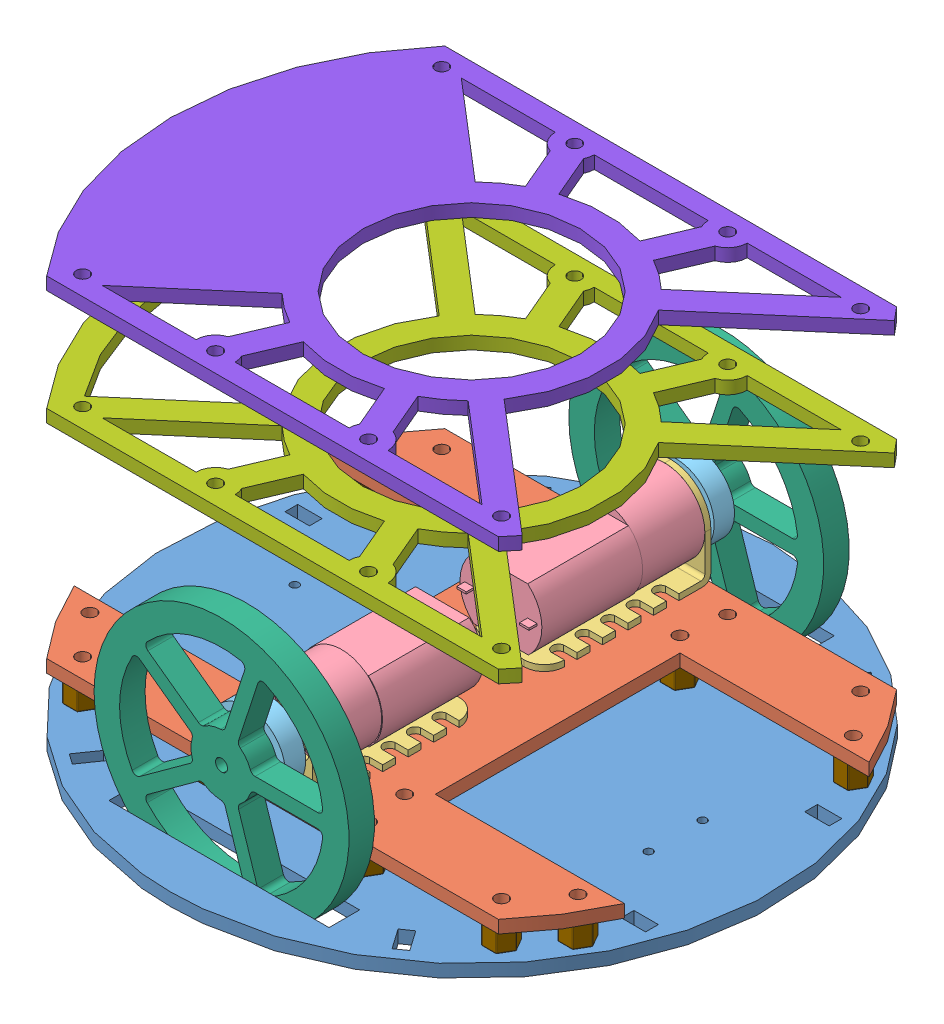
SolidWorks assembly Assembly, configuration Default. Lengths in mm.
Overall size (150 102.8 150).
30 component instances, 9 part files, 36 mates.
Components (placement in the parent):
- Bottom-1: Bottom [Default] at (46.4313 73.5336 122.3273) size (150 3.17 150)
- WheelPlatform-1: WheelPlatform [Default] at (46.4313 83.0586 122.3273) size (137.05 3.17 99.19)
- Pololu_bracket-1: Pololu_bracket [Default] at (36.4313 86.2336 171.9215) x (0 0 -1) z (1 0 0) size (41.5 21.5 20)
- Pololu_29to1-1: Pololu_29to1 [Default] at (46.4313 97.7336 154.7215) size (20.4 20 53.45)
- Pololu_4mm_MountingHub-1: Pololu_4mm_MountingHub [Default] at (46.4313 97.7336 178.2815) x (0 -1 0) z (0 0 -1) size (19.05 19.05 5.08)
- Wheel-1: Wheel [Default] at (46.4313 97.7336 184.6315) x (0 -1 0) z (1 0 0) size (63.5 6.35 63.5)
- Wheel-2: Wheel [Default] at (46.4313 97.7336 60.0231) x (0 1 0) z (1 0 0) size (63.5 6.35 63.5)
- Pololu_4mm_MountingHub-2: Pololu_4mm_MountingHub [Default] at (46.4313 97.7336 71.4531) x (0 -1 0) z (0 0 -1) size (19.05 19.05 5.08)
- Pololu_29to1-2: Pololu_29to1 [Default] at (46.4313 97.7336 89.9331) x (-1 0 0) z (0 0 -1) size (20.4 20 53.45)
- Pololu_bracket-2: Pololu_bracket [Default] at (56.4313 86.2336 72.7331) x (0 0 1) z (-1 0 0) size (41.5 21.5 20)
- CanBottom-1: CanBottom [Default] at (46.4313 137.0336 122.3273) size (133.96 3.17 99.19)
- CanMiddle-1: CanMiddle [Default] at (46.4313 165.6086 122.3273) size (133.96 3.17 99.19)
- Standoff-1: Standoff [Default] at (-5.749 76.7086 167.0571) size (7.25 6.35 6.35)
- Standoff-2: Standoff [Default] at (-14.3605 76.7086 156.6173) size (7.25 6.35 6.35)
- Standoff-3: Standoff [Default] at (27.3813 76.7086 167.0571) x (0.5 0 0.866025) z (-0.866025 0 0.5) size (7.25 6.35 6.35)
- Standoff-4: Standoff [Default] at (28.8195 76.7086 156.6173) size (7.25 6.35 6.35)
- Standoff-5: Standoff [Default] at (98.6116 76.7086 167.0571) x (-1 0 0) z (0 0 -1) size (7.25 6.35 6.35)
- Standoff-6: Standoff [Default] at (107.2231 76.7086 156.6173) x (-1 0 0) z (0 0 -1) size (7.25 6.35 6.35)
- Standoff-7: Standoff [Default] at (65.4813 76.7086 167.0571) x (-0.5 0 0.866025) z (-0.866025 0 -0.5) size (7.25 6.35 6.35)
- Standoff-8: Standoff [Default] at (64.0431 76.7086 156.6173) x (-1 0 0) z (0 0 -1) size (7.25 6.35 6.35)
- Standoff-9: Standoff [Default] at (46.4313 76.7086 133.8215) size (7.25 6.35 6.35)
- Standoff-10: Standoff [Default] at (98.6116 76.7086 77.5974) x (-1 0 0) z (0 0 -1) size (7.25 6.35 6.35)
- Standoff-11: Standoff [Default] at (107.2231 76.7086 88.0373) x (-1 0 0) z (0 0 -1) size (7.25 6.35 6.35)
- Standoff-12: Standoff [Default] at (65.4813 76.7086 77.5974) x (-0.5 0 -0.866025) z (0.866025 0 -0.5) size (7.25 6.35 6.35)
- Standoff-13: Standoff [Default] at (64.0431 76.7086 88.0373) x (-1 0 0) z (0 0 -1) size (7.25 6.35 6.35)
- Standoff-14: Standoff [Default] at (-5.749 76.7086 77.5974) size (7.25 6.35 6.35)
- Standoff-15: Standoff [Default] at (27.3813 76.7086 77.5974) x (0.5 0 -0.866025) z (0.866025 0 0.5) size (7.25 6.35 6.35)
- Standoff-16: Standoff [Default] at (-14.3605 76.7086 88.0373) size (7.25 6.35 6.35)
- Standoff-17: Standoff [Default] at (28.8195 76.7086 88.0373) size (7.25 6.35 6.35)
- Standoff-18: Standoff [Default] at (46.4313 76.7086 110.8331) size (7.25 6.35 6.35)
Mates (geometry in assembly coordinates):
- Concentric1: concentric aligned: cylinder of Bottom-1 through (46.4313 76.7086 122.3273) axis (0 -1 0) radius 75; cylinder of WheelPlatform-1 through (46.4313 86.2336 122.3273) axis (0 -1 0) radius 75
- Distance1: distance = 6.35 mm anti-aligned: plane of Bottom-1 through (46.4313 76.7086 122.3273) normal (0 1 0); plane of WheelPlatform-1 through (46.4313 83.0586 122.3273) normal (0 -1 0)
- Parallel1: parallel aligned: plane of Bottom-1 through (19.0182 18.1804 177.6465) normal (0 0 1); plane of WheelPlatform-1 through (-9.8307 -32.2979 171.9215) normal (0 0 1)
- Concentric2: concentric anti-aligned: cylinder of Pololu_bracket-1 through (46.4313 97.7336 130.4215) axis (0 0 1) radius 3.75; cylinder of Pololu_29to1-1 through (46.4313 97.7336 173.2015) axis (0 0 -1) radius 3.5
- Concentric3: concentric aligned: cylinder of Pololu_bracket-1 through (46.4313 105.2336 130.4215) axis (0 0 1) radius 1.45; cylinder of Pololu_29to1-1 through (46.4313 105.2336 170.4215) axis (0 0 1) radius 1.025
- Coincident8: coincident anti-aligned: plane of Pololu_bracket-1 through (56.4313 87.7336 170.4215) normal (0 0 -1); plane of Pololu_29to1-1 through (46.4313 97.7336 170.4215) normal (0 0 1)
- Concentric4: concentric anti-aligned: cylinder of Pololu_29to1-1 through (46.4313 97.7336 181.0715) axis (0 0 -1) radius 2; cylinder of Pololu_4mm_MountingHub-1 through (46.4313 97.7336 173.2015) axis (0 0 1) radius 2
- Coincident9: coincident anti-aligned: plane of Pololu_29to1-1 through (46.4313 97.7336 154.7215) normal (1 0 0); plane of Pololu_4mm_MountingHub-1
- Coincident10: coincident anti-aligned: plane of Pololu_29to1-1 through (46.4313 97.7336 173.2015) normal (0 0 1); plane of Pololu_4mm_MountingHub-1 through (46.4313 97.7336 173.2015) normal (0 0 -1)
- Concentric6: concentric anti-aligned: cylinder of Pololu_29to1-1 through (46.4313 97.7336 181.0715) axis (0 0 -1) radius 2; cylinder of Wheel-1 through (46.4313 97.7336 178.2815) axis (0 0 1) radius 1.5
- Coincident11: coincident anti-aligned: plane of Pololu_4mm_MountingHub-1 through (46.4313 97.7336 178.2815) normal (0 0 1); plane of Wheel-1 through (46.4313 97.7336 178.2815) normal (0 0 -1)
- Coincident12: coincident anti-aligned: plane of Pololu_4mm_MountingHub-1; plane of Wheel-1 through (46.4313 97.7336 184.6315) normal (1 0 0)
- Coincident14: coincident anti-aligned: plane of WheelPlatform-1 through (46.4313 86.2336 122.3273) normal (0 1 0); plane of Pololu_bracket-1 through (56.4313 86.2336 171.9215) normal (0 -1 0)
- Coincident15: coincident anti-aligned: plane of Bottom-1 through (46.4313 73.5336 181.4565) normal (0 0 1); plane of Wheel-1
- Coincident16: coincident aligned: plane of WheelPlatform-1 through (46.4313 83.0586 122.3273) normal (1 0 0); plane of Pololu_29to1-1 through (46.4313 97.7336 154.7215) normal (1 0 0)
- Concentric7: concentric aligned: cylinder of Bottom-1 through (46.4313 76.7086 122.3273) axis (0 -1 0) radius 75; cylinder of CanBottom-1 through (46.4313 140.2086 122.3273) axis (0 -1 0) radius 75
- Distance2: distance = 50.8 mm anti-aligned: plane of WheelPlatform-1 through (46.4313 86.2336 122.3273) normal (0 1 0); plane of CanBottom-1 through (46.4313 137.0336 122.3273) normal (0 -1 0)
- Parallel2: parallel aligned: plane of WheelPlatform-1 through (-9.8307 -32.2979 171.9215) normal (0 0 1); plane of CanBottom-1 through (-9.8307 21.6771 171.9215) normal (0 0 1)
- Concentric8: concentric aligned: cylinder of Bottom-1 through (46.4313 76.7086 122.3273) axis (0 -1 0) radius 75; cylinder of CanMiddle-1 through (46.4313 168.7836 122.3273) axis (0 -1 0) radius 75
- Coincident19: coincident aligned: plane of CanBottom-1 through (-9.8307 21.6771 171.9215) normal (0 0 1); plane of CanMiddle-1 through (-9.8307 50.2521 171.9215) normal (0 0 1)
- Distance3: distance = 25.4 mm anti-aligned: plane of CanBottom-1 through (46.4313 140.2086 122.3273) normal (0 1 0); plane of CanMiddle-1 through (46.4313 165.6086 122.3273) normal (0 -1 0)
- Concentric9: concentric anti-aligned: cylinder of Bottom-1 through (-5.749 69.0434 167.0571) axis (0 1 0) radius 1.5875; cylinder of Standoff-1 through (-5.749 83.0586 167.0571) axis (0 -1 0) radius 1.4732
- Coincident21: coincident anti-aligned: plane of Bottom-1 through (46.4313 76.7086 122.3273) normal (0 1 0); plane of Standoff-1 through (-5.749 76.7086 167.0571) normal (0 -1 0)
- Parallel3: parallel aligned: plane of WheelPlatform-1 through (-9.8307 -32.2979 171.9215) normal (0 0 1); plane of Standoff-1 through (-7.5821 83.0586 170.2321) normal (0 0 1)
- Concentric10: concentric anti-aligned: cylinder of Bottom-1 through (-14.3605 69.0434 156.6173) axis (0 1 0) radius 1.5875; cylinder of Standoff-2 through (-14.3605 83.0586 156.6173) axis (0 -1 0) radius 1.4732
- Coincident23: coincident anti-aligned: plane of Bottom-1 through (46.4313 76.7086 122.3273) normal (0 1 0); plane of Standoff-2 through (-14.3605 76.7086 156.6173) normal (0 -1 0)
- Parallel4: parallel aligned: plane of Standoff-1 through (-7.5821 83.0586 170.2321) normal (0 0 1); plane of Standoff-2 through (-16.1936 83.0586 159.7923) normal (0 0 1)
- Concentric11: concentric anti-aligned: cylinder of Bottom-1 through (27.3813 69.0434 167.0571) axis (0 1 0) radius 1.5875; cylinder of Standoff-3 through (27.3813 83.0586 167.0571) axis (0 -1 0) radius 1.4732
- Coincident24: coincident anti-aligned: plane of Bottom-1 through (46.4313 76.7086 122.3273) normal (0 1 0); plane of Standoff-3 through (27.3813 76.7086 167.0571) normal (0 -1 0)
- Parallel5: parallel aligned: plane of Bottom-1 through (19.0182 18.1804 177.6465) normal (0 0 1); plane of Standoff-3 through (25.5482 83.0586 170.2321) normal (0 0 1)
- Concentric12: concentric anti-aligned: cylinder of Bottom-1 through (28.8195 69.0434 156.6173) axis (0 1 0) radius 1.5875; cylinder of Standoff-4 through (28.8195 83.0586 156.6173) axis (0 -1 0) radius 1.4732
- Coincident26: coincident anti-aligned: plane of Bottom-1 through (46.4313 76.7086 122.3273) normal (0 1 0); plane of Standoff-4 through (28.8195 76.7086 156.6173) normal (0 -1 0)
- Parallel6: parallel aligned: plane of Standoff-3 through (25.5482 83.0586 170.2321) normal (0 0 1); plane of Standoff-4 through (26.9864 83.0586 159.7923) normal (0 0 1)
- Coincident28: coincident anti-aligned: plane of Bottom-1 through (46.4313 76.7086 122.3273) normal (0 1 0); plane of Standoff-9 through (46.4313 76.7086 133.8215) normal (0 -1 0)
- Concentric13: concentric anti-aligned: cylinder of Bottom-1 through (46.4313 69.0434 133.8215) axis (0 1 0) radius 1.5875; cylinder of Standoff-9 through (46.4313 83.0586 133.8215) axis (0 -1 0) radius 1.4732
- Parallel7: parallel aligned: plane of Bottom-1 through (19.0182 18.1804 177.6465) normal (0 0 1); plane of Standoff-9 through (44.5982 83.0586 136.9965) normal (0 0 1)
